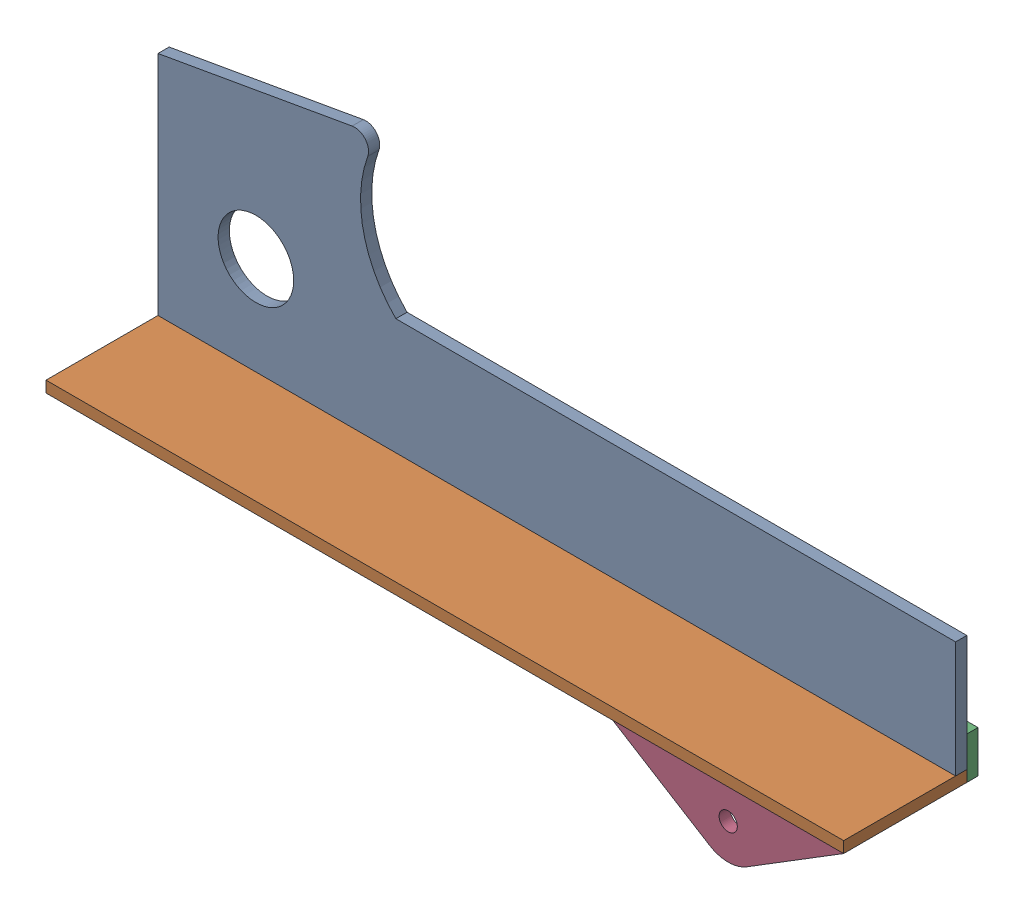
SolidWorks assembly ТП.016.03.05.00 - Ложемент, configuration Правый. Lengths in mm.
Overall size (285 120.43 48).
4 component instances, 4 part files, 12 mates.
Components (placement in the parent):
- ТП.016.03.05.01 - Ложемент бок (4мм)-1: ТП.016.03.05.01 - Ложемент бок (4мм) [--] at origin size (285 93.13 4)
- ТП.016.03.05.02 - Ложемент низ (4мм)-1: ТП.016.03.05.02 - Ложемент низ (4мм) [--] at (250 -35 -4) size (285 4 44)
- ТП.016.03.05.03 - Хомут связки (4мм)-1: ТП.016.03.05.03 - Хомут связки (4мм) [--] at (250 -39 -4) size (82.5 38.3 4)
- ТП.016.03.05.04 - Шайба связки (4мм)-1: ТП.016.03.05.04 - Шайба связки (4мм) [--] at (250 -39 40) size (82.5 23.3 4)
Mates (geometry in assembly coordinates):
- Совпадение1: coincident: plane of ТП.016.03.05.01 - Ложемент бок (4мм)-1 through (0 -35 -4) normal (0 -1 0); plane of ТП.016.03.05.02 - Ложемент низ (4мм)-1 through (250 -35 -4) normal (0 1 0)
- Совпадение2: coincident: plane of ТП.016.03.05.01 - Ложемент бок (4мм)-1 through (250 -35 -4) normal (1 0 0); plane of ТП.016.03.05.02 - Ложемент низ (4мм)-1 through (250 -39 40) normal (1 0 0)
- Совпадение3: coincident: plane of ТП.016.03.05.01 - Ложемент бок (4мм)-1 through (75.3946 35.3104 -4) normal (0 0 -1); plane of ТП.016.03.05.02 - Ложемент низ (4мм)-1 through (-35 -39 -4) normal (0 0 -1)
- Совпадение4: coincident: plane of ТП.016.03.05.01 - Ложемент бок (4мм)-1 through (75.3946 35.3104 0) normal (0 0 1); plane of ТП.016.03.05.02 - Ложемент низ (4мм)-1 through (-35 -39 0) normal (0 0 1)
- Совпадение5: coincident: plane of ТП.016.03.05.01 - Ложемент бок (4мм)-1 through (75.3946 35.3104 -4) normal (0 0 -1); plane of ТП.016.03.05.03 - Хомут связки (4мм)-1 through (208.7492 -49.65 -4) normal (0 0 1)
- Совпадение6: coincident: plane of ТП.016.03.05.01 - Ложемент бок (4мм)-1 through (250 -35 -4) normal (1 0 0); plane of ТП.016.03.05.03 - Хомут связки (4мм)-1 through (250 -24 -8) normal (1 0 0)
- Совпадение7: coincident: line of ТП.016.03.05.02 - Ложемент низ (4мм)-1 through (250 -39 40) axis (0 0 -1); line of ТП.016.03.05.03 - Хомут связки (4мм)-1 through (250 -39 -8) axis (0 0 1)
- Совпадение8: coincident: plane of ТП.016.03.05.01 - Ложемент бок (4мм)-1 through (75.3946 35.3104 0) normal (0 0 1); plane of ТП.016.03.05.03 - Хомут связки (4мм)-1 through (208.7492 -49.65 0) normal (0 0 -1)
- Совпадение9: coincident: plane of ТП.016.03.05.02 - Ложемент низ (4мм)-1 through (250 -39 -4) normal (0 -1 0); plane of ТП.016.03.05.04 - Шайба связки (4мм)-1 through (167.4983 -39 36) normal (0 1 0)
- Совпадение10: coincident: plane of ТП.016.03.05.02 - Ложемент низ (4мм)-1 through (-35 -39 40) normal (0 0 1); plane of ТП.016.03.05.04 - Шайба связки (4мм)-1 through (208.7492 -49.65 40) normal (0 0 1)
- Совпадение11: coincident: line of ТП.016.03.05.02 - Ложемент низ (4мм)-1 through (250 -39 40) axis (0 0 -1); line of ТП.016.03.05.04 - Шайба связки (4мм)-1 through (250 -39 36) axis (0 0 1)
- Совпадение12: coincident: plane of ТП.016.03.05.02 - Ложемент низ (4мм)-1 through (-35 -39 -4) normal (0 0 -1); plane of ТП.016.03.05.04 - Шайба связки (4мм)-1 through (208.7492 -49.65 -44) normal (0 0 -1)
